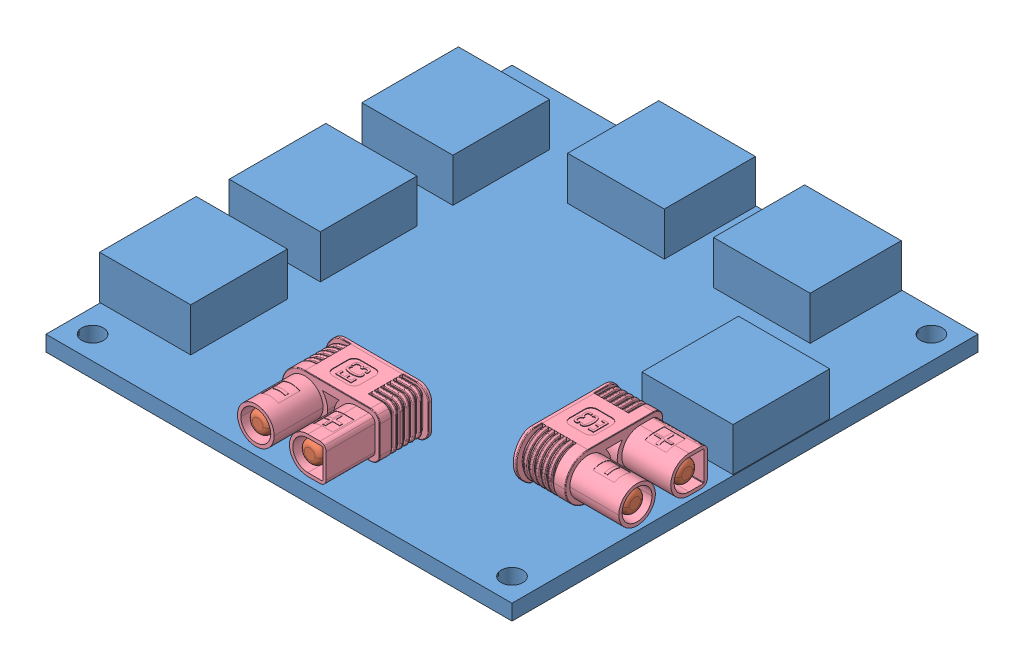
SolidWorks assembly board_all, configuration Default. Lengths in mm.
Overall size (76.33 10.86 76.2).
25 component instances, 4 part files, 5 mates.
Components (placement in the parent):
- board-1: board [Default] at (10.8409 -3.4389 -6.6254) size (76.33 9.64 76.2)
- EC3 Connector Plug-1: EC3 Connector Plug [Default] at (33.1734 3.3808 31.4746) size (17 8.32 16)
  - EC3 Connector Plug.stp-1: EC3 Connector Plug.stp [Default] at origin size (17 8.32 16)
    - EC3 Connector Assembly.stp-1: EC3 Connector Assembly.stp [Default] at origin size (17 8.32 16)
      - Plug.stp-1: Plug.stp [Default] at (-17.6267 -0.0297 -12.35) size (4.75 4.75 12.54)
        - 3-5mm Bullit Plug.stp-1: 3-5mm Bullit Plug.stp [Default] at origin size (4.75 4.75 12.54)
          - Pin.stp-1: Pin.stp [Default] at origin size (4.75 4.75 12.54)
          - Spring.stp-1: Spring.stp [Default] at origin size (4.11 4.11 5.4)
      - Plug.stp-2: Plug.stp [Default] at (-26.1267 -0.0297 -12.35) size (4.75 4.75 12.54)
        - 3-5mm Bullit Plug.stp-1: 3-5mm Bullit Plug.stp [Default] at origin size (4.75 4.75 12.54)
          - Pin.stp-1: Pin.stp [Default] at origin size (4.75 4.75 12.54)
          - Spring.stp-1: Spring.stp [Default] at origin size (4.11 4.11 5.4)
      - Shell2.stp-1: Shell2.stp [Default] at origin size (17 8.32 16)
- EC3 Connector Plug-2: EC3 Connector Plug [Default] at (48.9409 2.8808 -15.1035) x (0 0 -1) z (1 0 0) size (17 8.32 16)
  - EC3 Connector Plug.stp-1: EC3 Connector Plug.stp [Default] at origin size (17 8.32 16)
    - EC3 Connector Assembly.stp-1: EC3 Connector Assembly.stp [Default] at origin size (17 8.32 16)
      - Plug.stp-1: Plug.stp [Default] at (-17.6267 -0.0297 -12.35) size (4.75 4.75 12.54)
        - 3-5mm Bullit Plug.stp-1: 3-5mm Bullit Plug.stp [Default] at origin size (4.75 4.75 12.54)
          - Pin.stp-1: Pin.stp [Default] at origin size (4.75 4.75 12.54)
          - Spring.stp-1: Spring.stp [Default] at origin size (4.11 4.11 5.4)
      - Plug.stp-2: Plug.stp [Default] at (-26.1267 -0.0297 -12.35) size (4.75 4.75 12.54)
        - 3-5mm Bullit Plug.stp-1: 3-5mm Bullit Plug.stp [Default] at origin size (4.75 4.75 12.54)
          - Pin.stp-1: Pin.stp [Default] at origin size (4.75 4.75 12.54)
          - Spring.stp-1: Spring.stp [Default] at origin size (4.11 4.11 5.4)
      - Shell2.stp-1: Shell2.stp [Default] at origin size (17 8.32 16)
Mates (geometry in assembly coordinates):
- Coincident1: coincident anti-aligned: plane of board-1 through (10.8409 -0.8989 -6.6254) normal (0 1 0); plane of EC3 Connector Plug-2/EC3 Connector Plug.stp-1/EC3 Connector Assembly.stp-1/Shell2.stp-1 through (48.9409 -0.8989 0.8976) normal (0 -1 0)
- Coincident2: coincident aligned: plane of board-1 through (48.9409 -0.8989 -44.7254) normal (1 0 0); plane of EC3 Connector Plug-2/EC3 Connector Plug.stp-1/EC3 Connector Assembly.stp-1/Shell2.stp-1 through (48.9409 2.8808 9.5687) normal (1 0 0)
- Distance1: distance = 4.318 mm anti-aligned: plane of board-1 through (33.9139 6.2011 -4.7954) normal (0 0 1); plane of EC3 Connector Plug-2/EC3 Connector Plug.stp-1/EC3 Connector Assembly.stp-1/Shell2.stp-1 through (48.9409 2.8511 -0.4774) normal (0 0 -1)
- Coincident4: coincident anti-aligned: plane of board-1 through (10.8409 -0.8989 -6.6254) normal (0 1 0); plane of EC3 Connector Plug-1/EC3 Connector Plug.stp-1/EC3 Connector Assembly.stp-1/Shell2.stp-1 through (16.6722 -0.8989 15.4746) normal (0 -1 0)
- Coincident6: coincident aligned: plane of board-1 through (48.9409 -0.8989 31.4746) normal (0 0 1); plane of EC3 Connector Plug-1/EC3 Connector Plug.stp-1/EC3 Connector Assembly.stp-1/Shell2.stp-1 through (8.5011 3.3808 31.4746) normal (0 0 1)
